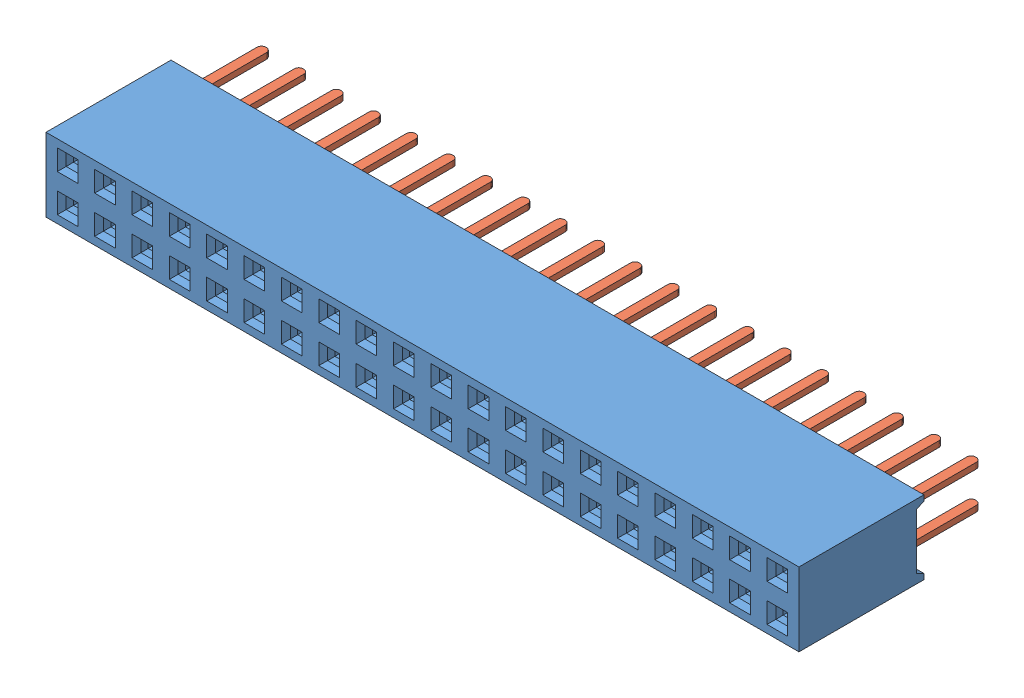
SolidWorks assembly 装配体1, configuration 默认. Lengths in mm.
Overall size (51.2 5 13.5).
41 component instances, 2 part files, 2 mates.
Components (placement in the parent):
- 2.54排母-1: 2.54排母 [默认] at (38.1143 -72.4007 -4.25) size (51.2 5 8.5)
- Y端2.54-5-2: Y端2.54-5 [默认] at (32.7645 3.0076 0.1261) x (0 0 1) z (0 -1 0) size (11.6 2.02 0.4)
- Y端2.54-5-3: Y端2.54-5 [默认] at (30.2245 3.0076 0.1261) x (0 0 1) z (0 -1 0) size (11.6 2.02 0.4)
- Y端2.54-5-4: Y端2.54-5 [默认] at (27.6845 3.0076 0.1261) x (0 0 1) z (0 -1 0) size (11.6 2.02 0.4)
- Y端2.54-5-5: Y端2.54-5 [默认] at (25.1445 3.0076 0.1261) x (0 0 1) z (0 -1 0) size (11.6 2.02 0.4)
- Y端2.54-5-6: Y端2.54-5 [默认] at (22.6045 3.0076 0.1261) x (0 0 1) z (0 -1 0) size (11.6 2.02 0.4)
- Y端2.54-5-7: Y端2.54-5 [默认] at (20.0645 3.0076 0.1261) x (0 0 1) z (0 -1 0) size (11.6 2.02 0.4)
- Y端2.54-5-8: Y端2.54-5 [默认] at (17.5245 3.0076 0.1261) x (0 0 1) z (0 -1 0) size (11.6 2.02 0.4)
- Y端2.54-5-9: Y端2.54-5 [默认] at (14.9845 3.0076 0.1261) x (0 0 1) z (0 -1 0) size (11.6 2.02 0.4)
- Y端2.54-5-10: Y端2.54-5 [默认] at (12.4445 3.0076 0.1261) x (0 0 1) z (0 -1 0) size (11.6 2.02 0.4)
- Y端2.54-5-11: Y端2.54-5 [默认] at (9.9045 3.0076 0.1261) x (0 0 1) z (0 -1 0) size (11.6 2.02 0.4)
- Y端2.54-5-12: Y端2.54-5 [默认] at (7.3645 3.0076 0.1261) x (0 0 1) z (0 -1 0) size (11.6 2.02 0.4)
- Y端2.54-5-13: Y端2.54-5 [默认] at (4.8245 3.0076 0.1261) x (0 0 1) z (0 -1 0) size (11.6 2.02 0.4)
- Y端2.54-5-14: Y端2.54-5 [默认] at (2.2845 3.0076 0.1261) x (0 0 1) z (0 -1 0) size (11.6 2.02 0.4)
- Y端2.54-5-15: Y端2.54-5 [默认] at (-0.2555 3.0076 0.1261) x (0 0 1) z (0 -1 0) size (11.6 2.02 0.4)
- Y端2.54-5-16: Y端2.54-5 [默认] at (-2.7955 3.0076 0.1261) x (0 0 1) z (0 -1 0) size (11.6 2.02 0.4)
- Y端2.54-5-17: Y端2.54-5 [默认] at (-5.3355 3.0076 0.1261) x (0 0 1) z (0 -1 0) size (11.6 2.02 0.4)
- Y端2.54-5-18: Y端2.54-5 [默认] at (-7.8755 3.0076 0.1261) x (0 0 1) z (0 -1 0) size (11.6 2.02 0.4)
- Y端2.54-5-19: Y端2.54-5 [默认] at (-10.4155 3.0076 0.1261) x (0 0 1) z (0 -1 0) size (11.6 2.02 0.4)
- Y端2.54-5-20: Y端2.54-5 [默认] at (-12.9555 3.0076 0.1261) x (0 0 1) z (0 -1 0) size (11.6 2.02 0.4)
- Y端2.54-5-21: Y端2.54-5 [默认] at (-15.4955 3.0076 0.1261) x (0 0 1) z (0 -1 0) size (11.6 2.02 0.4)
- Y端2.54-5-22: Y端2.54-5 [默认] at (32.7645 0.4676 0.1261) x (0 0 1) z (0 -1 0) size (11.6 2.02 0.4)
- Y端2.54-5-23: Y端2.54-5 [默认] at (30.2245 0.4676 0.1261) x (0 0 1) z (0 -1 0) size (11.6 2.02 0.4)
- Y端2.54-5-24: Y端2.54-5 [默认] at (27.6845 0.4676 0.1261) x (0 0 1) z (0 -1 0) size (11.6 2.02 0.4)
- Y端2.54-5-25: Y端2.54-5 [默认] at (25.1445 0.4676 0.1261) x (0 0 1) z (0 -1 0) size (11.6 2.02 0.4)
- Y端2.54-5-26: Y端2.54-5 [默认] at (22.6045 0.4676 0.1261) x (0 0 1) z (0 -1 0) size (11.6 2.02 0.4)
- Y端2.54-5-27: Y端2.54-5 [默认] at (20.0645 0.4676 0.1261) x (0 0 1) z (0 -1 0) size (11.6 2.02 0.4)
- Y端2.54-5-28: Y端2.54-5 [默认] at (17.5245 0.4676 0.1261) x (0 0 1) z (0 -1 0) size (11.6 2.02 0.4)
- Y端2.54-5-29: Y端2.54-5 [默认] at (14.9845 0.4676 0.1261) x (0 0 1) z (0 -1 0) size (11.6 2.02 0.4)
- Y端2.54-5-30: Y端2.54-5 [默认] at (12.4445 0.4676 0.1261) x (0 0 1) z (0 -1 0) size (11.6 2.02 0.4)
- Y端2.54-5-31: Y端2.54-5 [默认] at (9.9045 0.4676 0.1261) x (0 0 1) z (0 -1 0) size (11.6 2.02 0.4)
- Y端2.54-5-32: Y端2.54-5 [默认] at (7.3645 0.4676 0.1261) x (0 0 1) z (0 -1 0) size (11.6 2.02 0.4)
- Y端2.54-5-33: Y端2.54-5 [默认] at (4.8245 0.4676 0.1261) x (0 0 1) z (0 -1 0) size (11.6 2.02 0.4)
- Y端2.54-5-34: Y端2.54-5 [默认] at (2.2845 0.4676 0.1261) x (0 0 1) z (0 -1 0) size (11.6 2.02 0.4)
- Y端2.54-5-35: Y端2.54-5 [默认] at (-0.2555 0.4676 0.1261) x (0 0 1) z (0 -1 0) size (11.6 2.02 0.4)
- Y端2.54-5-36: Y端2.54-5 [默认] at (-2.7955 0.4676 0.1261) x (0 0 1) z (0 -1 0) size (11.6 2.02 0.4)
- Y端2.54-5-37: Y端2.54-5 [默认] at (-5.3355 0.4676 0.1261) x (0 0 1) z (0 -1 0) size (11.6 2.02 0.4)
- Y端2.54-5-38: Y端2.54-5 [默认] at (-7.8755 0.4676 0.1261) x (0 0 1) z (0 -1 0) size (11.6 2.02 0.4)
- Y端2.54-5-39: Y端2.54-5 [默认] at (-10.4155 0.4676 0.1261) x (0 0 1) z (0 -1 0) size (11.6 2.02 0.4)
- Y端2.54-5-40: Y端2.54-5 [默认] at (-12.9555 0.4676 0.1261) x (0 0 1) z (0 -1 0) size (11.6 2.02 0.4)
- Y端2.54-5-41: Y端2.54-5 [默认] at (-15.4955 0.4676 0.1261) x (0 0 1) z (0 -1 0) size (11.6 2.02 0.4)
Mates (geometry in assembly coordinates):
- 重合2: coincident anti-aligned: plane of 2.54排母-1 through (22.1258 3.0076 3.45) normal (0 -1 0); plane of Y端2.54-5-2 through (32.7645 3.0076 0.1261) normal (0 1 0)
- 重合3: coincident aligned: plane of 2.54排母-1 through (38.1143 -72.4007 -3.75) normal (0 0 -1); plane of Y端2.54-5-2 through (22.1169 2.6076 -3.75) normal (0 0 -1)
